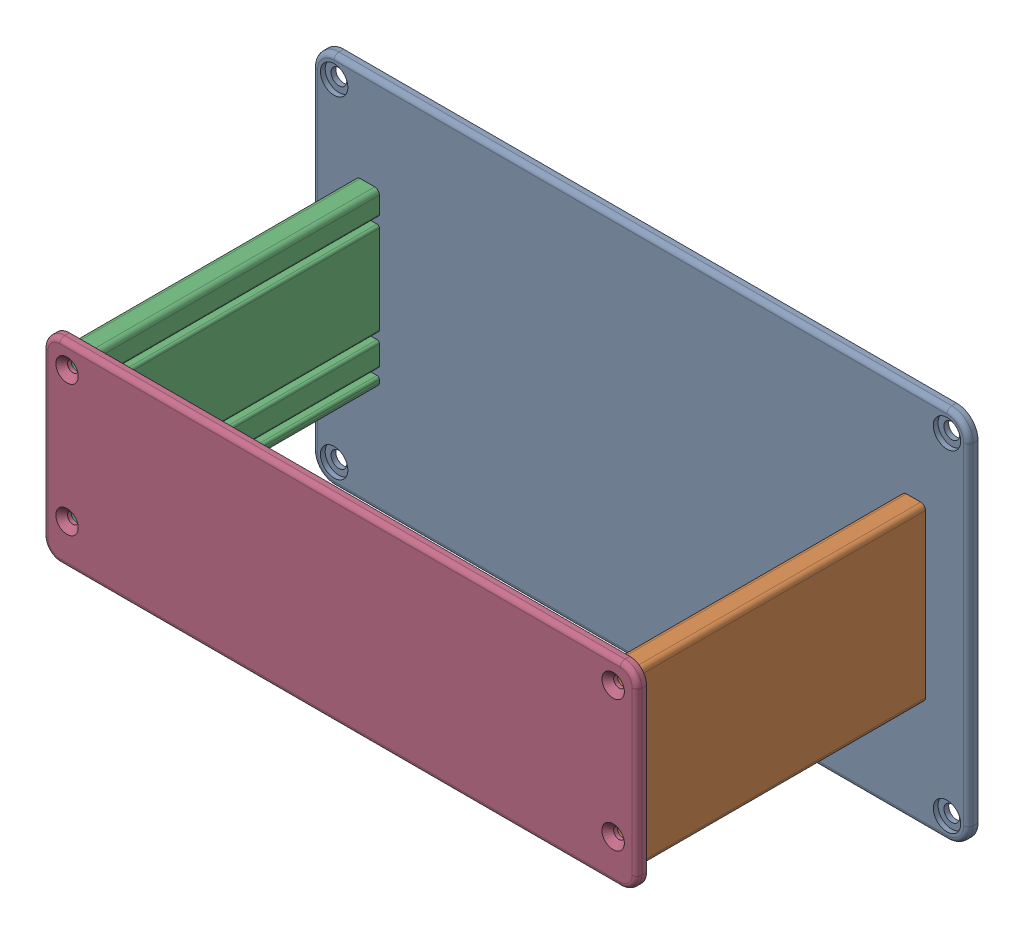
SolidWorks assembly Assemblage, configuration Défaut. Lengths in mm.
Overall size (275 157 130).
4 component instances, 3 part files, 12 mates.
Components (placement in the parent):
- socle-1: socle [Défaut] at origin size (275 157 4)
- pilier-1: pilier [Défaut] at (116.4104 2.8911 4) x (0 1 0) z (0 0 1) size (72 10 122)
- pilier-2: pilier [Défaut] at (-116.4104 2.8911 126) x (0 1 0) z (0 0 -1) size (72 10 122)
- couvercle-1: couvercle [Défaut] at (0 3 126) size (249 82 4)
Mates (geometry in assembly coordinates):
- Coaxiale3: concentric anti-aligned: circle of socle-1; circle of pilier-1
- Coïncidente1: coincident anti-aligned: plane of socle-1 through (0 0 4) normal (0 0 1); plane of pilier-1 through (116.4104 2.8911 4) normal (0 0 -1)
- Coaxiale4: concentric anti-aligned: circle of socle-1; circle of pilier-1
- Coïncidente4: coincident anti-aligned: plane of socle-1 through (0 0 4) normal (0 0 1); plane of pilier-2 through (-116.4104 2.8911 4) normal (0 0 -1)
- Coaxiale7: concentric aligned: circle of socle-1; circle of pilier-2
- Coaxiale8: concentric aligned: circle of socle-1; circle of pilier-2
- Coïncidente6: coincident anti-aligned: plane of pilier-2 through (-116.4104 2.8911 126) normal (0 0 1); plane of couvercle-1 through (0 3 126) normal (0 0 -1)
- Coïncidente7: coincident anti-aligned: plane of pilier-1 through (116.4104 2.8911 126) normal (0 0 1); plane of couvercle-1 through (0 3 126) normal (0 0 -1)
- Coaxiale9: concentric anti-aligned: circle of pilier-2; circle of couvercle-1
- Coaxiale11: concentric anti-aligned: circle of pilier-2; circle of couvercle-1
- Coaxiale12: concentric aligned: circle of pilier-1; circle of couvercle-1
- Coaxiale13: concentric aligned: circle of pilier-1; circle of couvercle-1
